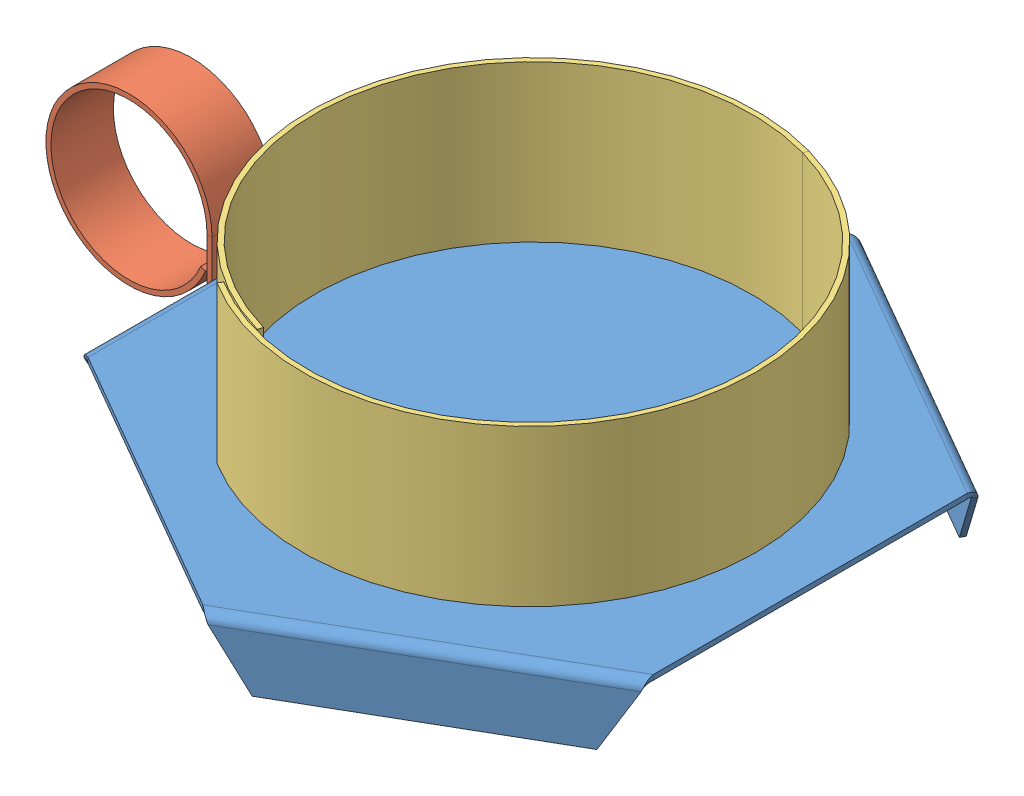
SolidWorks assembly Ensamblaje1, configuration Predeterminado. Lengths in mm.
Overall size (118.17 35.49 105.74).
3 component instances, 3 part files, 5 mates.
Components (placement in the parent):
- base-1: base [Predeterminado] at (6.8467 2.0588 105.739) size (91.57 10.49 105.74)
- handle-1: handle [Predeterminado] at (-39.7533 -8.429 100.739) size (26.6 28.91 10)
- holder-1: holder [Predeterminado] at (6.8467 2.0588 105.739) x (-0.96269 0 -0.270608) z (0.270608 0 -0.96269) size (72.1 25 72.6)
Mates (geometry in assembly coordinates):
- Coincidente1: coincident: plane of base-1 through (6.8467 2.0588 105.739) normal (0 1 0); circle of holder-1
- Coincidente3: coincident: point of base-1; point of holder-1
- Coincidente4: coincident: line of base-1 through (-38.9533 -8.429 85.5317) axis (0 0 1); line of handle-1 through (-38.9533 -8.429 110.739) axis (0 0 -1)
- Coincidente5: coincident: moEndPointRef_w of base-1; moEndPointRef_w of handle-1
- Coincidente6: coincident anti-aligned: plane of base-1 through (-38.9533 46.571 105.739) normal (-1 0 0); plane of handle-1 through (-38.9533 -8.429 110.739) normal (1 0 0)
